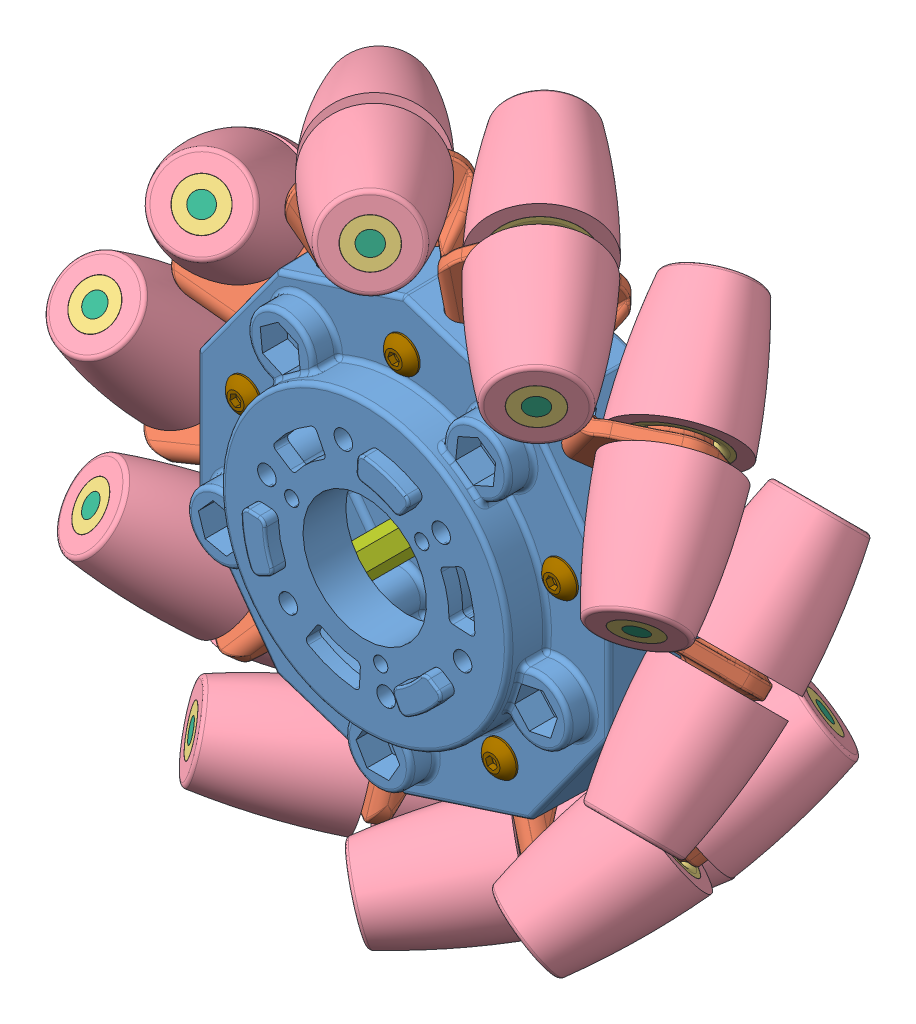
SolidWorks assembly 6_Mecanum_Wheel_Right_217-2586, configuration Default. Lengths in mm.
Overall size (159.68 163.12 66.52).
98 component instances, 9 part files, 0 mates.
Components (placement in the parent):
- 217-2586-001 Rev4-1: 217-2586-001 Rev4 [Default] at (0 0 -6.35) size (95.78 100.46 28.55)
- 217-2586-001 Rev4-2: 217-2586-001 Rev4 [Default] at (0 0 6.35) x (-0.809017 0.587785 0) z (0 0 -1) size (95.78 100.46 28.55)
- 217-2586-002 Rev2-1: 217-2586-002 Rev2 [Default] at (-12.8179 39.4495 0) x (0.951057 0.309017 0) z (-0.309017 0.951057 0) size (26.84 25.28 30.09)
- 217-2586-003 Rev2-1: 217-2586-003 Rev2 [Default] at (-23.0486 57.9718 -4.0062) x (0.656917 0.263835 -0.706294) z (-0.340891 0.939492 0.033887) size (19.46 28.57 19.46)
- 217-2586-003 Rev2-2: 217-2586-003 Rev2 [Default] at (-15.4283 60.4478 4.0062) x (-0.134846 0.975606 -0.173232) z (0.72771 -0.021148 -0.685559) size (19.46 28.57 19.46)
- 217-2586-004 Rev1-1: 217-2586-004 Rev1 [Default] at (-19.6233 59.0847 -0.4047) x (0.203589 -0.97318 0.107105) z (-0.711546 -0.071932 0.698948) size (25.9 28.58 25.9)
- 217-2586-004 Rev1-2: 217-2586-004 Rev1 [Default] at (-18.8527 59.3351 0.4056) x (-0.440555 -0.64952 0.619705) z (0.594691 -0.72827 -0.340537) size (25.9 28.58 25.9)
- 217-2586-005 Rev2-1: 217-2586-005 Rev2 [Default] at (-25.2573 57.2541 -6.3286) x (0.672499 0.218508 0.707107) z (-0.568604 -0.459036 0.682624) size (8.5 8 8)
- 217-2586-005 Rev2-2: 217-2586-005 Rev2 [Default] at (-13.2196 61.1654 6.3286) x (0.672499 0.218508 0.707107) z (-0.568604 -0.459036 0.682624) size (8.5 8 8)
- 217-2586-007 Rev1-1: 217-2586-007 Rev1 [Default] at (-19.2384 59.2098 0) x (0.672499 0.218508 0.707107) z (-0.649691 0.631892 0.422627) size (61.72 5 5)
- 217-2586-008 Rev1-1: 217-2586-008 Rev1 [Default] at (-17.6961 -15.9337 -0.127) x (-0.309017 -0.951057 0) z (0 0 -1) size (7.33 6.35 31.75)
- NUT-832-NYLOCK-1: NUT-832-NYLOCK [Default] at (-36.6157 11.8972 -13.6563) x (-0.997378 -0.072366 0) z (0.072366 -0.997378 0) size (10.2 5.86 8.12)
- SCREW-832-1250-1: SCREW-832-1250 [Default] at (-36.6157 11.8972 14.9098) x (0 0 -1) z (-0.996377 0.08505 0) size (33.96 7.92 7.92)
- NUT-832-NYLOCK-2: NUT-832-NYLOCK [Default] at (0 38.5 -13.6563) x (-0.377031 0.926201 0) z (-0.926201 -0.377031 0) size (10.2 5.86 8.12)
- NUT-832-NYLOCK-3: NUT-832-NYLOCK [Default] at (36.6157 11.8972 -13.6563) x (0.76436 0.644789 0) z (-0.644789 0.76436 0) size (10.2 5.86 8.12)
- NUT-832-NYLOCK-4: NUT-832-NYLOCK [Default] at (22.6297 -31.1472 -13.6563) x (0.849431 -0.527699 0) z (0.527699 0.849431 0) size (10.2 5.86 8.12)
- NUT-832-NYLOCK-5: NUT-832-NYLOCK [Default] at (-22.6297 -31.1472 -13.6563) x (-0.239383 -0.970925 0) z (0.970925 -0.239383 0) size (10.2 5.86 8.12)
- SCREW-832-1250-2: SCREW-832-1250 [Default] at (0 38.5 14.9098) x (0 0 -1) z (-0.22701 0.973892 0) size (33.96 7.92 7.92)
- SCREW-832-1250-3: SCREW-832-1250 [Default] at (36.6157 11.8972 14.9098) x (0 0 -1) z (0.856077 0.516849 0) size (33.96 7.92 7.92)
- SCREW-832-1250-4: SCREW-832-1250 [Default] at (22.6297 -31.1472 14.9098) x (0 0 -1) z (0.756095 -0.654462 0) size (33.96 7.92 7.92)
- SCREW-832-1250-5: SCREW-832-1250 [Default] at (-22.6297 -31.1472 14.9098) x (0 0 -1) z (-0.388785 -0.921329 0) size (33.96 7.92 7.92)
- 217-2586-002 Rev2-2: 217-2586-002 Rev2 [Default] at (12.8179 39.4495 0) x (0.951057 -0.309017 0) z (0.309017 0.951057 0) size (26.84 25.28 30.09)
- 217-2586-002 Rev2-3: 217-2586-002 Rev2 [Default] at (33.5577 24.3811 0) x (0.587785 -0.809017 0) z (0.809017 0.587785 0) size (26.84 25.28 30.09)
- 217-2586-002 Rev2-4: 217-2586-002 Rev2 [Default] at (41.4796 0 0) x (0 -1 0) z (1 0 0) size (26.84 25.28 30.09)
- 217-2586-002 Rev2-5: 217-2586-002 Rev2 [Default] at (33.5577 -24.3811 0) x (-0.587785 -0.809017 0) z (0.809017 -0.587785 0) size (26.84 25.28 30.09)
- 217-2586-002 Rev2-6: 217-2586-002 Rev2 [Default] at (12.8179 -39.4495 0) x (-0.951057 -0.309017 0) z (0.309017 -0.951057 0) size (26.84 25.28 30.09)
- 217-2586-002 Rev2-7: 217-2586-002 Rev2 [Default] at (-12.8179 -39.4495 0) x (-0.951057 0.309017 0) z (-0.309017 -0.951057 0) size (26.84 25.28 30.09)
- 217-2586-002 Rev2-8: 217-2586-002 Rev2 [Default] at (-33.5577 -24.3811 0) x (-0.587785 0.809017 0) z (-0.809017 -0.587785 0) size (26.84 25.28 30.09)
- 217-2586-002 Rev2-9: 217-2586-002 Rev2 [Default] at (-41.4796 0 0) x (0 1 0) z (-1 0 0) size (26.84 25.28 30.09)
- 217-2586-002 Rev2-10: 217-2586-002 Rev2 [Default] at (-33.5577 24.3811 0) x (0.587785 0.809017 0) z (-0.809017 0.587785 0) size (26.84 25.28 30.09)
- 217-2586-004 Rev1-3: 217-2586-004 Rev1 [Default] at (19.6242 59.0844 0.4056) x (-0.738195 -0.266521 0.619705) z (0.053049 -0.938733 -0.340537) size (25.9 28.58 25.9)
- 217-2586-004 Rev1-4: 217-2586-004 Rev1 [Default] at (50.6053 36.2655 0.4056) x (-0.75387 0.21828 0.619705) z (-0.508857 -0.790633 -0.340537) size (25.9 28.58 25.9)
- 217-2586-004 Rev1-5: 217-2586-004 Rev1 [Default] at (62.2568 -0.4056 0.4056) x (-0.481592 0.619705 0.619705) z (-0.876396 -0.340537 -0.340537) size (25.9 28.58 25.9)
- 217-2586-004 Rev1-6: 217-2586-004 Rev1 [Default] at (50.1284 -36.9218 0.4056) x (-0.025362 0.784425 0.619705) z (-0.909182 0.239632 -0.340537) size (25.9 28.58 25.9)
- 217-2586-004 Rev1-7: 217-2586-004 Rev1 [Default] at (18.8527 -59.3351 0.4056) x (0.440555 0.64952 0.619705) z (-0.594691 0.72827 -0.340537) size (25.9 28.58 25.9)
- 217-2586-004 Rev1-8: 217-2586-004 Rev1 [Default] at (-19.6242 -59.0844 0.4056) x (0.738195 0.266521 0.619705) z (-0.053049 0.938733 -0.340537) size (25.9 28.58 25.9)
- 217-2586-004 Rev1-9: 217-2586-004 Rev1 [Default] at (-50.6053 -36.2655 0.4056) x (0.75387 -0.21828 0.619705) z (0.508857 0.790633 -0.340537) size (25.9 28.58 25.9)
- 217-2586-004 Rev1-10: 217-2586-004 Rev1 [Default] at (-62.2568 0.4056 0.4056) x (0.481592 -0.619705 0.619705) z (0.876396 0.340537 -0.340537) size (25.9 28.58 25.9)
- 217-2586-004 Rev1-11: 217-2586-004 Rev1 [Default] at (-50.1284 36.9218 0.4056) x (0.025362 -0.784425 0.619705) z (0.909182 -0.239632 -0.340537) size (25.9 28.58 25.9)
- 217-2586-008 Rev1-2: 217-2586-008 Rev1 [Default] at (-22.647 7.3585 -0.127) x (-0.978148 -0.207912 0) z (0 0 -1) size (7.33 6.35 31.75)
- 217-2586-008 Rev1-3: 217-2586-008 Rev1 [Default] at (-4.9509 23.2921 -0.127) x (-0.669131 0.743145 0) z (0 0 -1) size (7.33 6.35 31.75)
- 217-2586-008 Rev1-4: 217-2586-008 Rev1 [Default] at (17.6961 15.9337 -0.127) x (0.309017 0.951057 0) z (0 0 -1) size (7.33 6.35 31.75)
- 217-2586-008 Rev1-5: 217-2586-008 Rev1 [Default] at (22.647 -7.3585 -0.127) x (0.978148 0.207912 0) z (0 0 -1) size (7.33 6.35 31.75)
- 217-2586-008 Rev1-6: 217-2586-008 Rev1 [Default] at (4.9509 -23.2921 -0.127) x (0.669131 -0.743145 0) z (0 0 -1) size (7.33 6.35 31.75)
- 217-2586-005 Rev2-3: 217-2586-005 Rev2 [Default] at (25.2573 57.2541 6.3286) x (0.672499 -0.218508 0.707107) z (-0.729825 -0.037151 0.682624) size (8.5 8 8)
- 217-2586-005 Rev2-4: 217-2586-005 Rev2 [Default] at (54.0867 31.4737 6.3286) x (0.415627 -0.572061 0.707107) z (-0.612278 0.398924 0.682624) size (8.5 8 8)
- 217-2586-005 Rev2-5: 217-2586-005 Rev2 [Default] at (62.2568 -6.3286 6.3286) x (0 -0.707107 0.707107) z (-0.260861 0.682624 0.682624) size (8.5 8 8)
- 217-2586-005 Rev2-6: 217-2586-005 Rev2 [Default] at (46.647 -41.7136 6.3286) x (-0.415627 -0.572061 0.707107) z (0.190195 0.705585 0.682624) size (8.5 8 8)
- 217-2586-005 Rev2-7: 217-2586-005 Rev2 [Default] at (13.2196 -61.1654 6.3286) x (-0.672499 -0.218508 0.707107) z (0.568604 0.459036 0.682624) size (8.5 8 8)
- 217-2586-005 Rev2-8: 217-2586-005 Rev2 [Default] at (-25.2573 -57.2541 6.3286) x (-0.672499 0.218508 0.707107) z (0.729825 0.037151 0.682624) size (8.5 8 8)
- 217-2586-005 Rev2-9: 217-2586-005 Rev2 [Default] at (-54.0867 -31.4737 6.3286) x (-0.415627 0.572061 0.707107) z (0.612278 -0.398924 0.682624) size (8.5 8 8)
- 217-2586-005 Rev2-10: 217-2586-005 Rev2 [Default] at (-62.2568 6.3286 6.3286) x (0 0.707107 0.707107) z (0.260861 -0.682624 0.682624) size (8.5 8 8)
- 217-2586-005 Rev2-11: 217-2586-005 Rev2 [Default] at (-46.647 41.7136 6.3286) x (0.415627 0.572061 0.707107) z (-0.190195 -0.705585 0.682624) size (8.5 8 8)
- 217-2586-005 Rev2-12: 217-2586-005 Rev2 [Default] at (13.2196 61.1654 -6.3286) x (0.672499 -0.218508 0.707107) z (-0.729825 -0.037151 0.682624) size (8.5 8 8)
- 217-2586-005 Rev2-13: 217-2586-005 Rev2 [Default] at (46.647 41.7136 -6.3286) x (0.415627 -0.572061 0.707107) z (-0.612278 0.398924 0.682624) size (8.5 8 8)
- 217-2586-005 Rev2-14: 217-2586-005 Rev2 [Default] at (62.2568 6.3286 -6.3286) x (0 -0.707107 0.707107) z (-0.260861 0.682624 0.682624) size (8.5 8 8)
- 217-2586-005 Rev2-15: 217-2586-005 Rev2 [Default] at (54.0867 -31.4737 -6.3286) x (-0.415627 -0.572061 0.707107) z (0.190195 0.705585 0.682624) size (8.5 8 8)
- 217-2586-005 Rev2-16: 217-2586-005 Rev2 [Default] at (25.2573 -57.2541 -6.3286) x (-0.672499 -0.218508 0.707107) z (0.568604 0.459036 0.682624) size (8.5 8 8)
- 217-2586-005 Rev2-17: 217-2586-005 Rev2 [Default] at (-13.2196 -61.1654 -6.3286) x (-0.672499 0.218508 0.707107) z (0.729825 0.037151 0.682624) size (8.5 8 8)
- 217-2586-005 Rev2-18: 217-2586-005 Rev2 [Default] at (-46.647 -41.7136 -6.3286) x (-0.415627 0.572061 0.707107) z (0.612278 -0.398924 0.682624) size (8.5 8 8)
- 217-2586-005 Rev2-19: 217-2586-005 Rev2 [Default] at (-62.2568 -6.3286 -6.3286) x (0 0.707107 0.707107) z (0.260861 -0.682624 0.682624) size (8.5 8 8)
- 217-2586-005 Rev2-20: 217-2586-005 Rev2 [Default] at (-54.0867 31.4737 -6.3286) x (0.415627 0.572061 0.707107) z (-0.190195 -0.705585 0.682624) size (8.5 8 8)
- 217-2586-003 Rev2-3: 217-2586-003 Rev2 [Default] at (23.0486 57.9718 4.0062) x (0.464354 0.868542 -0.173232) z (0.5763 -0.444846 -0.685559) size (19.46 28.57 19.46)
- 217-2586-003 Rev2-4: 217-2586-003 Rev2 [Default] at (52.7216 33.3525 4.0062) x (0.886187 0.429725 -0.173232) z (0.204762 -0.698629 -0.685559) size (19.46 28.57 19.46)
- 217-2586-003 Rev2-5: 217-2586-003 Rev2 [Default] at (62.2568 -4.0062 4.0062) x (0.969526 -0.173232 -0.173232) z (-0.244988 -0.685559 -0.685559) size (19.46 28.57 19.46)
- 217-2586-003 Rev2-6: 217-2586-003 Rev2 [Default] at (48.012 -39.8348 4.0062) x (0.68254 -0.710021 -0.173232) z (-0.60116 -0.410628 -0.685559) size (19.46 28.57 19.46)
- 217-2586-003 Rev2-7: 217-2586-003 Rev2 [Default] at (15.4283 -60.4478 4.0062) x (0.134846 -0.975606 -0.173232) z (-0.72771 0.021148 -0.685559) size (19.46 28.57 19.46)
- 217-2586-003 Rev2-8: 217-2586-003 Rev2 [Default] at (-23.0486 -57.9718 4.0062) x (-0.464354 -0.868542 -0.173232) z (-0.5763 0.444846 -0.685559) size (19.46 28.57 19.46)
- 217-2586-003 Rev2-9: 217-2586-003 Rev2 [Default] at (-52.7216 -33.3525 4.0062) x (-0.886187 -0.429725 -0.173232) z (-0.204762 0.698629 -0.685559) size (19.46 28.57 19.46)
- 217-2586-003 Rev2-10: 217-2586-003 Rev2 [Default] at (-62.2568 4.0062 4.0062) x (-0.969526 0.173232 -0.173232) z (0.244988 0.685559 -0.685559) size (19.46 28.57 19.46)
- 217-2586-003 Rev2-11: 217-2586-003 Rev2 [Default] at (-48.012 39.8348 4.0062) x (-0.68254 0.710021 -0.173232) z (0.60116 0.410628 -0.685559) size (19.46 28.57 19.46)
- 217-2586-004 Rev1-12: 217-2586-004 Rev1 [Default] at (18.8536 59.3348 -0.4047) x (-0.407314 -0.906986 0.107105) z (-0.617933 0.360042 0.698948) size (25.9 28.58 25.9)
- 217-2586-004 Rev1-13: 217-2586-004 Rev1 [Default] at (50.129 36.921 -0.4047) x (-0.862637 -0.494354 0.107105) z (-0.288291 0.654492 0.698948) size (25.9 28.58 25.9)
- 217-2586-004 Rev1-14: 217-2586-004 Rev1 [Default] at (62.2568 0.4047 -0.4047) x (-0.988462 0.107105 0.107105) z (0.151469 0.698948 0.698948) size (25.9 28.58 25.9)
- 217-2586-004 Rev1-15: 217-2586-004 Rev1 [Default] at (50.6047 -36.2663 -0.4047) x (-0.736728 0.667653 0.107105) z (0.533372 0.47643 0.698948) size (25.9 28.58 25.9)
- 217-2586-004 Rev1-16: 217-2586-004 Rev1 [Default] at (19.6233 -59.0847 -0.4047) x (-0.203589 0.97318 0.107105) z (0.711546 0.071932 0.698948) size (25.9 28.58 25.9)
- 217-2586-004 Rev1-17: 217-2586-004 Rev1 [Default] at (-18.8536 -59.3348 -0.4047) x (0.407314 0.906986 0.107105) z (0.617933 -0.360042 0.698948) size (25.9 28.58 25.9)
- 217-2586-004 Rev1-18: 217-2586-004 Rev1 [Default] at (-50.129 -36.921 -0.4047) x (0.862637 0.494354 0.107105) z (0.288291 -0.654492 0.698948) size (25.9 28.58 25.9)
- 217-2586-004 Rev1-19: 217-2586-004 Rev1 [Default] at (-62.2568 -0.4047 -0.4047) x (0.988462 -0.107105 0.107105) z (-0.151469 -0.698948 0.698948) size (25.9 28.58 25.9)
- 217-2586-004 Rev1-20: 217-2586-004 Rev1 [Default] at (-50.6047 36.2663 -0.4047) x (0.736728 -0.667653 0.107105) z (-0.533372 -0.47643 0.698948) size (25.9 28.58 25.9)
- 217-2586-003 Rev2-12: 217-2586-003 Rev2 [Default] at (15.4283 60.4478 -4.0062) x (0.686535 -0.172679 -0.706294) z (0.276433 0.960435 0.033887) size (19.46 28.57 19.46)
- 217-2586-003 Rev2-13: 217-2586-003 Rev2 [Default] at (48.012 39.8348 -4.0062) x (0.45392 -0.543235 -0.706294) z (0.788169 0.614525 0.033887) size (19.46 28.57 19.46)
- 217-2586-003 Rev2-14: 217-2586-003 Rev2 [Default] at (62.2568 4.0062 -4.0062) x (0.047924 -0.706294 -0.706294) z (0.998851 0.033887 0.033887) size (19.46 28.57 19.46)
- 217-2586-003 Rev2-15: 217-2586-003 Rev2 [Default] at (52.7216 -33.3525 -4.0062) x (-0.376378 -0.599573 -0.706294) z (0.828006 -0.559695 0.033887) size (19.46 28.57 19.46)
- 217-2586-003 Rev2-16: 217-2586-003 Rev2 [Default] at (23.0486 -57.9718 -4.0062) x (-0.656917 -0.263835 -0.706294) z (0.340891 -0.939492 0.033887) size (19.46 28.57 19.46)
- 217-2586-003 Rev2-17: 217-2586-003 Rev2 [Default] at (-15.4283 -60.4478 -4.0062) x (-0.686535 0.172679 -0.706294) z (-0.276433 -0.960435 0.033887) size (19.46 28.57 19.46)
- 217-2586-003 Rev2-18: 217-2586-003 Rev2 [Default] at (-48.012 -39.8348 -4.0062) x (-0.45392 0.543235 -0.706294) z (-0.788169 -0.614525 0.033887) size (19.46 28.57 19.46)
- 217-2586-003 Rev2-19: 217-2586-003 Rev2 [Default] at (-62.2568 -4.0062 -4.0062) x (-0.047924 0.706294 -0.706294) z (-0.998851 -0.033887 0.033887) size (19.46 28.57 19.46)
- 217-2586-003 Rev2-20: 217-2586-003 Rev2 [Default] at (-52.7216 33.3525 -4.0062) x (0.376378 0.599573 -0.706294) z (-0.828006 0.559695 0.033887) size (19.46 28.57 19.46)
- 217-2586-007 Rev1-2: 217-2586-007 Rev1 [Default] at (19.2384 59.2098 0) x (0.672499 -0.218508 0.707107) z (-0.154194 0.89309 0.422627) size (61.72 5 5)
- 217-2586-007 Rev1-3: 217-2586-007 Rev1 [Default] at (50.3668 36.5937 0) x (0.415627 -0.572061 0.707107) z (0.4002 0.813158 0.422627) size (61.72 5 5)
- 217-2586-007 Rev1-4: 217-2586-007 Rev1 [Default] at (62.2568 0 0) x (0 -0.707107 0.707107) z (0.801731 0.422627 0.422627) size (61.72 5 5)
- 217-2586-007 Rev1-5: 217-2586-007 Rev1 [Default] at (50.3668 -36.5937 0) x (-0.415627 -0.572061 0.707107) z (0.897028 -0.129333 0.422627) size (61.72 5 5)
- 217-2586-007 Rev1-6: 217-2586-007 Rev1 [Default] at (19.2384 -59.2098 0) x (-0.672499 -0.218508 0.707107) z (0.649691 -0.631892 0.422627) size (61.72 5 5)
- 217-2586-007 Rev1-7: 217-2586-007 Rev1 [Default] at (-19.2384 -59.2098 0) x (-0.672499 0.218508 0.707107) z (0.154194 -0.89309 0.422627) size (61.72 5 5)
- 217-2586-007 Rev1-8: 217-2586-007 Rev1 [Default] at (-50.3668 -36.5937 0) x (-0.415627 0.572061 0.707107) z (-0.4002 -0.813158 0.422627) size (61.72 5 5)
- 217-2586-007 Rev1-9: 217-2586-007 Rev1 [Default] at (-62.2568 0 0) x (0 0.707107 0.707107) z (-0.801731 -0.422627 0.422627) size (61.72 5 5)
- 217-2586-007 Rev1-10: 217-2586-007 Rev1 [Default] at (-50.3668 36.5937 0) x (0.415627 0.572061 0.707107) z (-0.897028 0.129333 0.422627) size (61.72 5 5)
